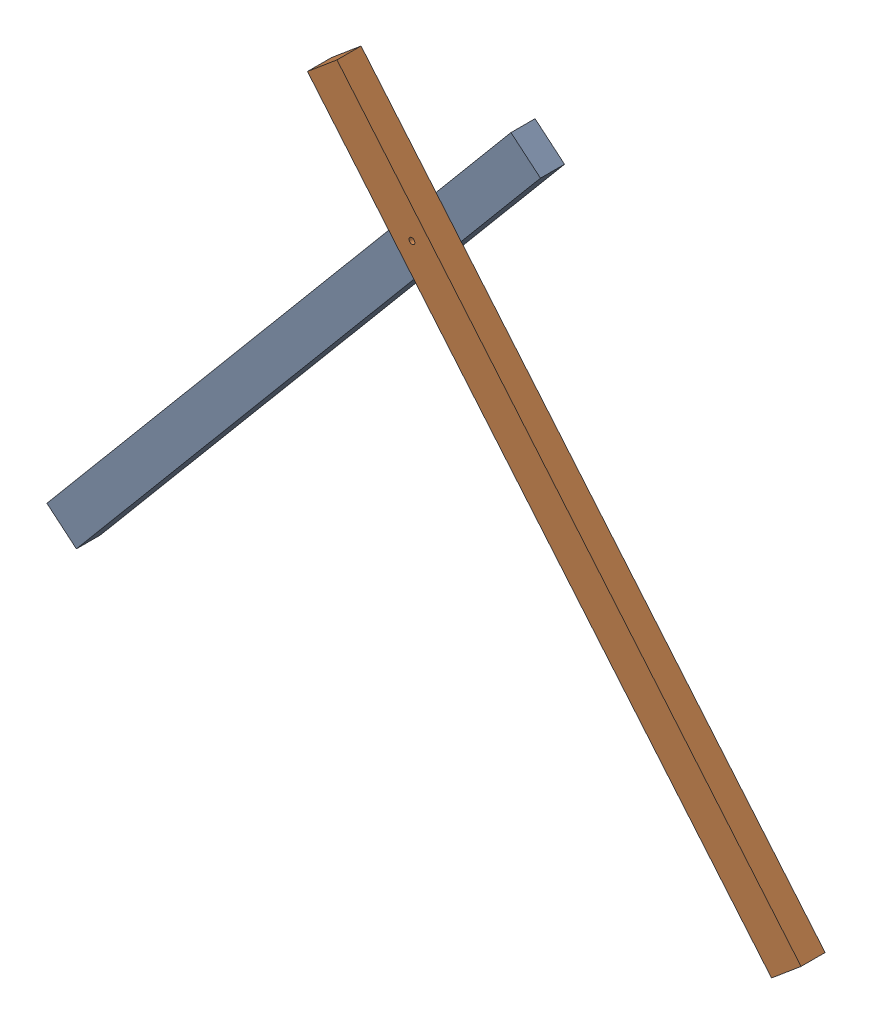
SolidWorks assembly КозлыСБ_СКС, configuration По умолчанию. Lengths in mm.
Overall size (1616.83 1200.49 100).
2 component instances, 1 part files, 8 mates.
Components (placement in the parent):
- Брус8050-1: Брус8050 [По умолчанию] at (-61.2836 51.423 0) x (0.642788 0.766044 0) z (-0.766044 0.642788 0) size (1500 50 80)
- Брус8050-2: Брус8050 [По умолчанию] at (1555.546 51.423 0) x (-0.642788 0.766044 0) z (0.766044 0.642788 0) size (1500 50 80)
Mates (geometry in assembly coordinates):
- Совпадение11: coincident: line of Брус8050-1 through (0 0 0) axis (0 0 -1)
- Совпадение12: coincident: line of Брус8050-1 through (0 0 0) axis (0 0 -1)
- Совпадение13: coincident anti-aligned: plane of Брус8050-1 through (902.8979 1200.4897 0) normal (0 0 1); plane of Брус8050-2 through (591.3646 1200.4897 0) normal (0 0 -1)
- Совпадение18: coincident: line of Брус8050-2 through (1494.2625 0 0) axis (0 0 1)
- Совпадение19: coincident: line of Брус8050-1 through (0 0 0) axis (0 0 -1)
- Совпадение20: coincident aligned: plane of Брус8050-1 through (902.8979 1200.4897 0) normal (0 0 1)
- Концентричный1: concentric anti-aligned: cylinder of Брус8050-1 through (747.1312 952.6253 0) axis (0 0 -1) radius 6; cylinder of Брус8050-2 through (747.1312 952.6253 0) axis (0 0 1) radius 6
- Угол6: planar angle = 1.396263 rad anti-aligned: plane of Брус8050-2 through (530.081 1149.0667 0) normal (-0.766044 -0.642788 0); plane of Брус8050-1 through (964.1814 1149.0667 0) normal (0.766044 -0.642788 0)
